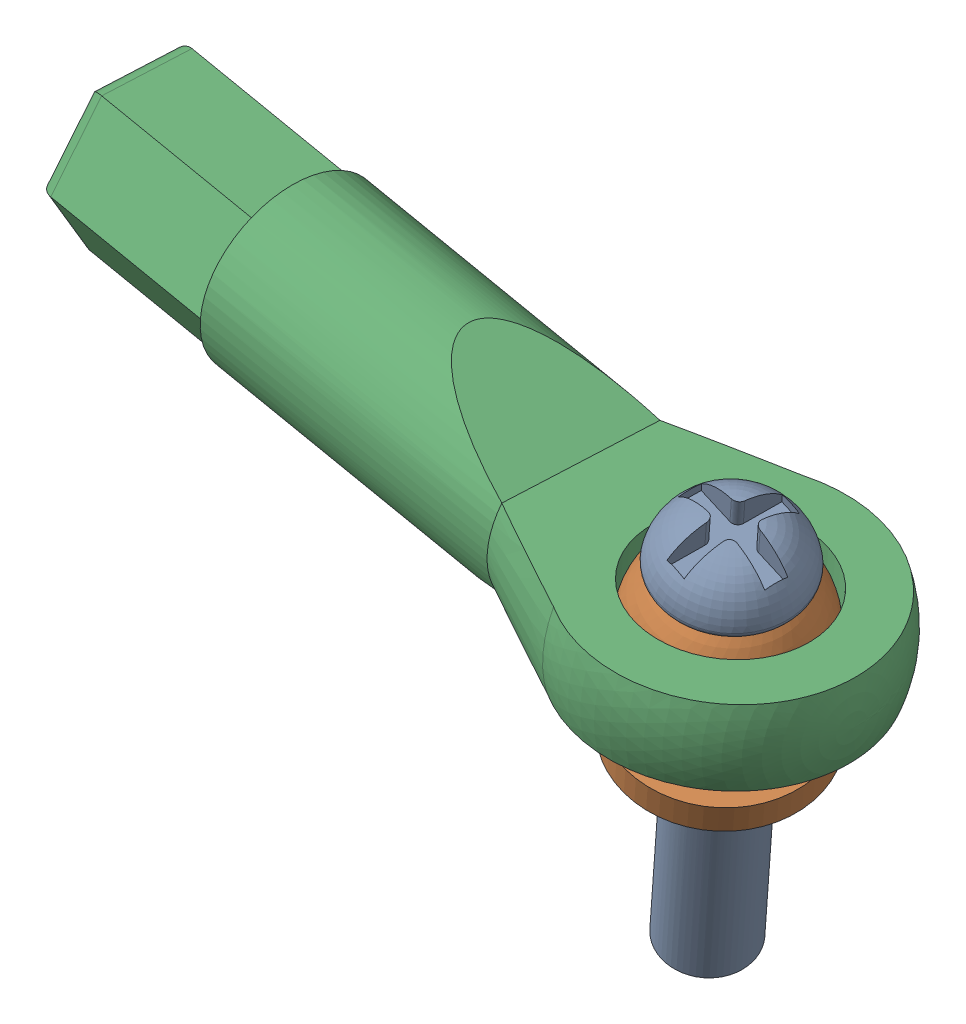
SolidWorks assembly Ball joint rod end assembly (F upper w geometry), configuration Default. Lengths in mm.
Overall size (30.19 19.84 12.28).
3 component instances, 3 part files, 6 mates.
Components (placement in the parent):
- ball joint bolt-1: ball joint bolt [Default] at (594.0464 904.6524 1275.9762) x (0.959593 -0.256977 0.114645) z (-0.155315 -0.14396 0.977319) size (4.76 18.12 4.76)
- Ball joint-1: Ball joint [Default] at (596.1582 913.2531 1277.5787) x (0.492708 -0.274817 0.82566) z (-0.837962 0.106007 0.535334) size (6.5 7 6.5)
- Rod End-1: Rod End [Default] at (573.4386 920.3276 1276.6394) x (0.075996 0.025894 -0.996772) z (-0.990646 0.115589 -0.072526) size (10 6.2 29)
Mates (geometry in assembly coordinates):
- Concentric2: concentric anti-aligned: circle of ball joint bolt-1; cylinder of Ball joint-1 through (596.1376 913.2214 1277.8099) axis (0.239226 0.962665 0.126675) radius 1.5
- Coincident4: coincident anti-aligned: plane of ball joint bolt-1 through (596.1315 920.4043 1278.4952) normal (-0.239226 -0.962665 -0.126675); plane of Ball joint-1 through (596.9785 920.3488 1277.3168) normal (0.239226 0.962665 0.126675)
- Concentric3: concentric: sphere of Ball joint-1; cylinder of Rod End-1 through (597.3841 919.0429 1278.4316) axis (-0.113337 -0.99296 -0.034436) radius 3
- Coincident11: coincident: point of Ball joint-1; point of Rod End-1
- Angle1: planar angle = 1.706112 rad aligned: line of Ball joint-1 through (596.1582 913.2531 1277.5787) axis (0.234644 0.955635 0.178055); line of Rod End-1 through (600.186 917.2067 1278.5976) axis (-0.990646 0.115589 -0.072526)
- Angle2: planar angle = 1.706112 rad aligned: line of Rod End-1 through (596.7388 917.3915 1284.6139) axis (0.075996 0.025894 -0.996772); line of Ball joint-1 through (596.1582 913.2531 1277.5787) axis (0.234644 0.955635 0.178055)
